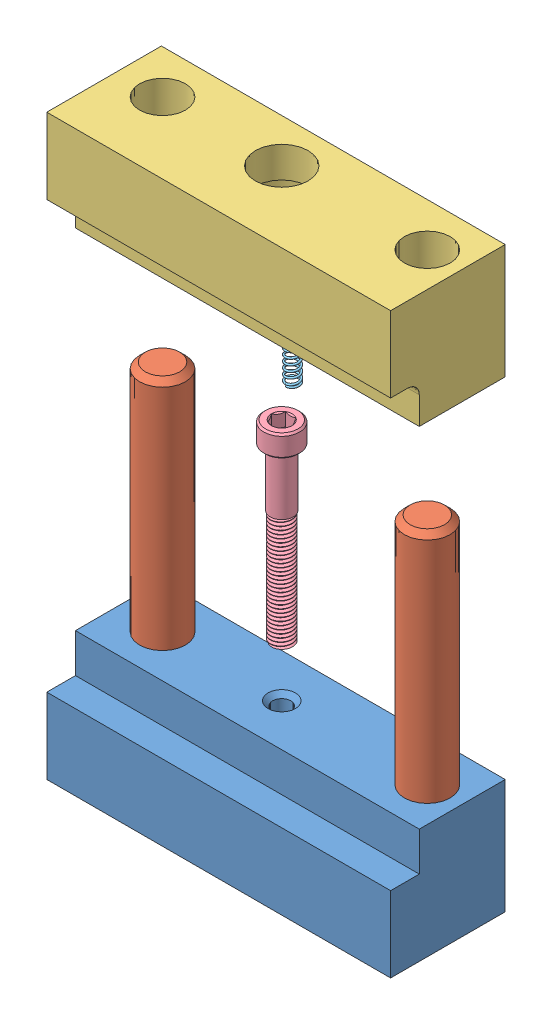
SolidWorks assembly Assembly, configuration Default. Lengths in mm.
Overall size (76.2 128.07 25.4).
6 component instances, 5 part files, 6 mates.
Components (placement in the parent):
- Bottom-1: Bottom [Default] at (-11.6997 -7.313 57.0559) size (76.2 25.4 25.4)
- dowel-1: dowel [Default] at (18.7803 17.706 47.6579) x (1 0 0) z (0 -1 0) size (10.16 10.16 70.87)
- Top-1: Top [Default] at (-13.4777 87.2309 57.0559) size (76.2 25.4 25.4)
- dowel-2: dowel [Default] at (-39.8937 17.706 47.6579) x (1 0 0) z (0 -1 0) size (10.16 10.16 70.87)
- 90128A951_ZNC-PLTD ALLOY STL SCKT HEAD CAP SCREW-2: 90128A951_ZNC-PLTD ALLOY STL SCKT HEAD CAP SCREW [90128A951] at (-13.4777 12.3374 47.6579) x (0 0 1) z (0 -1 0) size (7.92 7.92 43.85)
- 9657K266_STEEL COMPRESSION SPRING-2: 9657K266_STEEL COMPRESSION SPRING [9657K266] at (-14.1568 60.5349 44.5778) x (0 0 1) z (0 -1 0) size (3.18 3.18 12.7)
Mates (geometry in assembly coordinates):
- Coincident1: coincident anti-aligned: plane of Bottom-1 through (18.7803 -17.727 47.6579) normal (0 1 0); plane of dowel-1 through (18.7803 -17.727 47.6579) normal (0 -1 0)
- Concentric1: concentric anti-aligned: cylinder of Bottom-1 through (18.7803 -17.727 47.6579) axis (0 1 0) radius 5.08; cylinder of dowel-1 through (18.7803 53.139 47.6579) axis (0 -1 0) radius 5.08
- Coincident2: coincident anti-aligned: plane of Bottom-1 through (-39.8937 -17.727 47.6579) normal (0 1 0); plane of dowel-2 through (-39.8937 -17.727 47.6579) normal (0 -1 0)
- Concentric2: concentric anti-aligned: cylinder of Bottom-1 through (-39.8937 -17.727 47.6579) axis (0 1 0) radius 5.08; cylinder of dowel-2 through (-39.8937 53.139 47.6579) axis (0 -1 0) radius 5.08
- Concentric5: concentric anti-aligned: cylinder of Bottom-1 through (-13.4777 1.323 47.6579) axis (0 1 0) radius 2.0193; cylinder of 90128A951_ZNC-PLTD ALLOY STL SCKT HEAD CAP SCREW-2 through (-13.4777 12.3374 47.6579) axis (0 -1 0) radius 2.54
- Concentric6: concentric anti-aligned: cylinder of Top-1 through (-13.4777 78.5949 47.6579) axis (0 1 0) radius 5.842; cylinder of 90128A951_ZNC-PLTD ALLOY STL SCKT HEAD CAP SCREW-2 through (-13.4777 55.2634 47.6579) axis (0 -1 0) radius 3.9624
